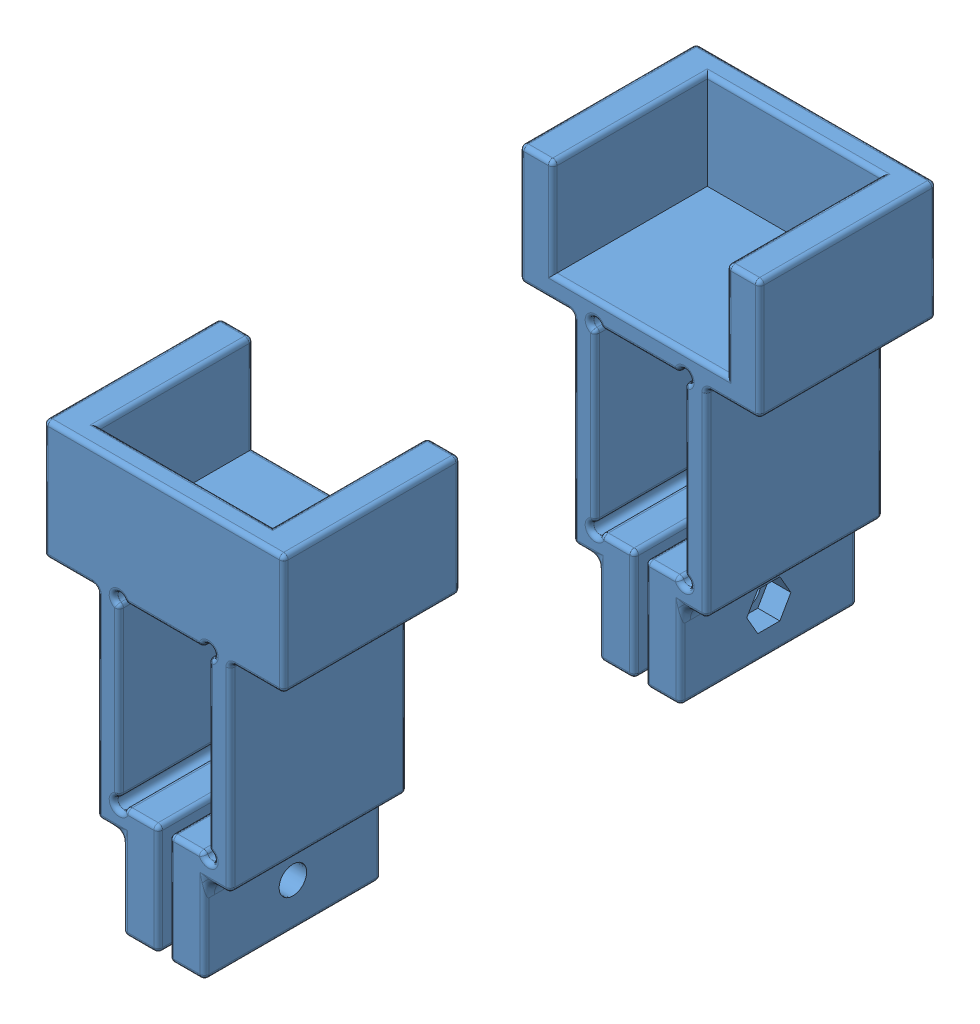
SolidWorks assembly Battery Holder, configuration Default. Lengths in mm.
Overall size (69.05 117.15 187.7).
2 component instances, 1 part files, 6 mates.
Components (placement in the parent):
- Part1^Battery Holder adjustable-4: Part1^Battery Holder adjustable [Default] at (0 0 -93.85) size (69.05 117.15 50.8)
- Part1^Battery Holder adjustable-3: Part1^Battery Holder adjustable [Default] at (0 0 93.85) x (-1 0 0) z (0 0 -1) size (69.05 117.15 50.8)
Mates (geometry in assembly coordinates):
- Coincident3: coincident aligned: plane of Part1^Battery Holder adjustable-4 through (0 0 -93.85) normal (0 1 0)
- Coincident4: coincident aligned: plane of Part1^Battery Holder adjustable-4 through (0 0 -93.85) normal (1 0 0)
- Coincident5: coincident: plane of Part1^Battery Holder adjustable-4 through (0 0 -87.5) normal (0 0 1)
- Coincident6: coincident aligned: plane of Part1^Battery Holder adjustable-3 through (0 0 93.85) normal (0 1 0)
- Coincident9: coincident: plane of Part1^Battery Holder adjustable-3 through (0 0 87.5) normal (0 0 -1)
- Coincident10: coincident anti-aligned: plane of Part1^Battery Holder adjustable-3 through (0 0 93.85) normal (-1 0 0)
